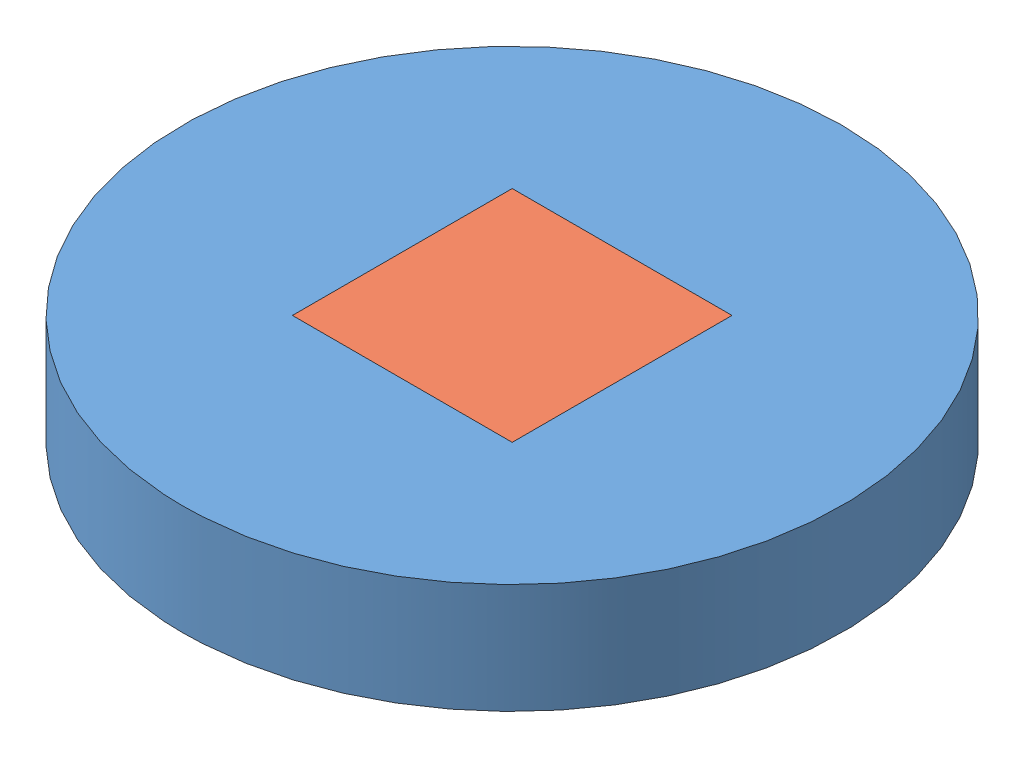
SolidWorks assembly Coin Assembly, configuration Default. Lengths in mm.
Overall size (30 5 30).
2 component instances, 2 part files, 3 mates.
Components (placement in the parent):
- Outer Cirlce Part-1: Outer Cirlce Part [Default] at (13.9362 14.4998 22.3681) size (30 5 30)
- Cicle Coin Conductive-1: Cicle Coin Conductive [Default] at (13.9362 19.4998 22.3681) x (-1 0 0) z (0 0 1) size (10 5 10)
Mates (geometry in assembly coordinates):
- Coincident1: coincident: plane of Outer Cirlce Part-1 through (13.9362 16.9998 27.3681) normal (0 1 0); plane of Cicle Coin Conductive-1 through (13.9362 16.9998 22.3681) normal (0 -1 0)
- Coincident2: coincident: plane of Outer Cirlce Part-1 through (18.9362 19.4998 27.3681) normal (-1 0 0); plane of Cicle Coin Conductive-1 through (18.9362 14.4998 27.3681) normal (1 0 0)
- Coincident3: coincident anti-aligned: plane of Outer Cirlce Part-1 through (18.9362 19.4998 27.3681) normal (0 0 -1); plane of Cicle Coin Conductive-1 through (8.9362 14.4998 27.3681) normal (0 0 1)
